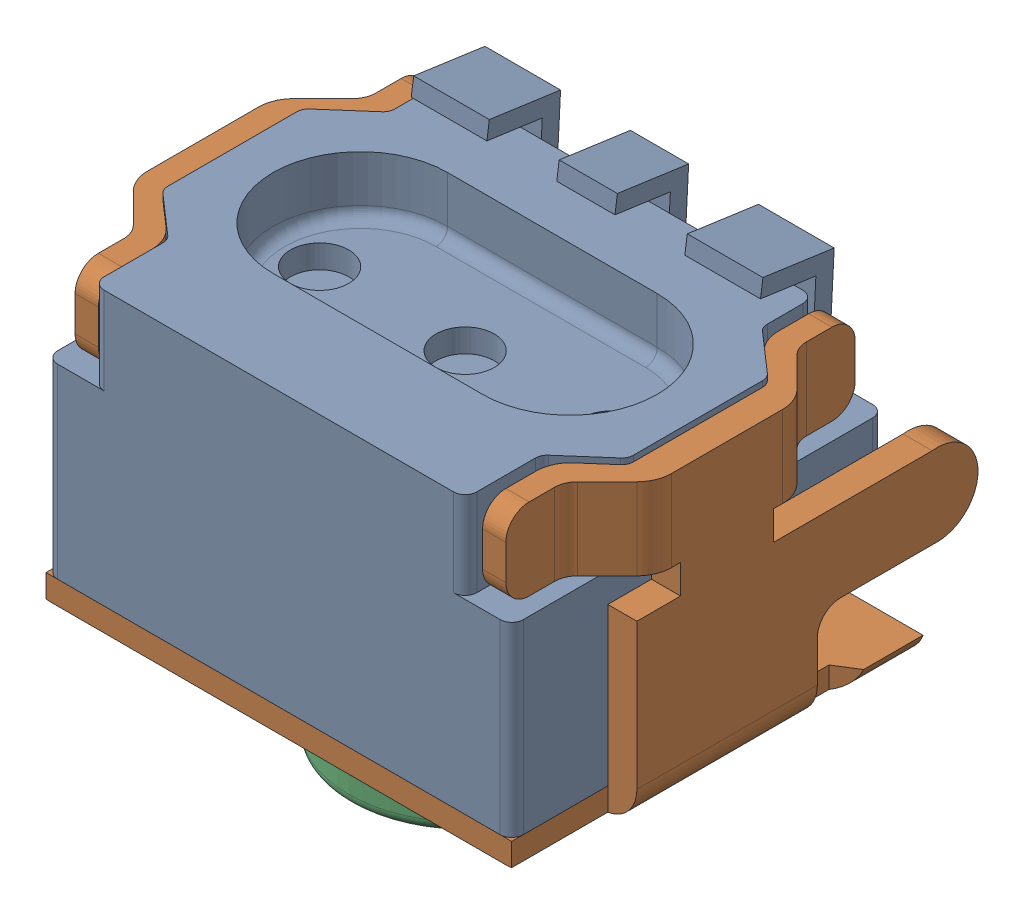
SolidWorks assembly J2, configuration Default. Lengths in mm.
Overall size (4.5 3.67 3.76).
4 component instances, 3 part files, 0 mates.
Components (placement in the parent):
- TL3340AF160QG-1: TL3340AF160QG [Default] at (131.1499 4.0499 1.65) x (-1 0 0) z (0 -1 0) size (4.5 3.76 3.67)
  - 2000862_Housing-1: 2000862_Housing [Default] x (-1 0 0) z (0 0 1) size (4 3.27 2.92)
  - 2000862_Bracket-1: 2000862_Bracket [Default] at (0 0 2.35) x (-1 0 0) z (0 0 1) size (4.5 3.76 2.5)
  - 2000862_Actuator-1: 2000862_Actuator [Default] at (0 0 1.85) x (-1 0 0) z (0 1 0) size (2.5 1.95 2.5)
